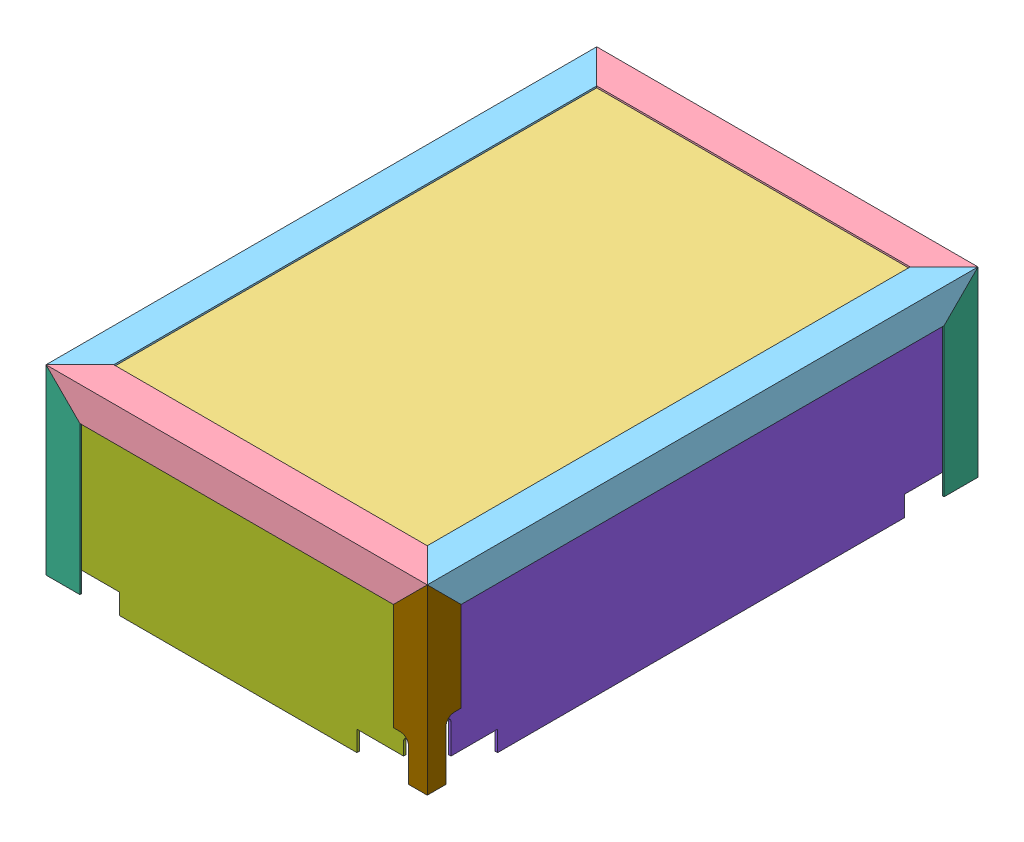
SolidWorks assembly couvercle, configuration Défaut. Lengths in mm.
Overall size (450 215 650).
13 component instances, 9 part files, 32 mates.
Components (placement in the parent):
- plaque_acrylique_680x210-2: plaque_acrylique_680x210 [Défaut] at (-694.8689 33.91 -173.3892) x (0 0 -1) z (1 0 0) size (640 210 3)
- plaque_acrylique_380x210-2: plaque_acrylique_380x210 [Défaut] at (-441.8689 33.91 -516.3892) size (440 210 3)
- plaque_acrylique_380x680-1: plaque_acrylique_380x680 [Défaut] at (-441.8689 138.91 -173.3892) x (1 0 0) z (0 1 0) size (440 640 3)
- eclisse_40x40x404_bisote_x2-1: eclisse_40x40x404_bisote_x2 [Défaut] at (-246.8689 123.7964 -498.3892) x (0 0 1) z (0 -1 0) size (40 450 40)
- eclisse_40x40x704_bisote_x2-1: eclisse_40x40x704_bisote_x2 [Défaut] at (-266.9825 123.91 -518.3892) x (0 -1 0) z (-1 0 0) size (40 650 40)
- eclisse_40x40x404_bisote_x2-2: eclisse_40x40x404_bisote_x2 [Défaut] at (-696.8689 123.7964 111.6108) x (0 0 -1) z (0 -1 0) size (40 450 40)
- eclisse_40x40x704_bisote_x2-2: eclisse_40x40x704_bisote_x2 [Défaut] at (-676.8689 123.7964 -518.3892) x (1 0 0) z (0 -1 0) size (40 650 40)
- eclisse_40x40x222_bisote_x1-1: eclisse_40x40x222_bisote_x1 [Défaut] at (-676.7552 143.91 -498.3892) x (0 0 1) z (1 0 0) size (40 215 40)
- eclisse_40x40x222_bisote_x1-2: eclisse_40x40x222_bisote_x1 [Défaut] at (-266.8689 143.91 -498.2755) x (-1 0 0) z (0 0 1) size (40 215 40)
- eclisse_40x40x222_bisote_x1-4: eclisse_40x40x222_bisote_x1 [Défaut] at (-676.8689 143.91 111.4972) x (1 0 0) z (0 0 -1) size (40 215 40)
- plaque_acrylique_380x210_Moteur-1: plaque_acrylique_380x210_Moteur [Défaut] at (-441.8689 33.91 126.6108) size (440 210 3)
- plaque_acrylique_680x210_moteur-1: plaque_acrylique_680x210_moteur [Défaut] at (-251.8689 33.91 -173.3892) x (0 0 -1) z (1 0 0) size (640 210 3)
- eclisse_40x40x222_bisote_x1_Moteur-1: eclisse_40x40x222_bisote_x1_Moteur [Défaut] at (-266.9825 143.91 111.6108) x (0 0 -1) z (-1 0 0) size (40 215 40)
Mates (geometry in assembly coordinates):
- Coïncidente1: coincident anti-aligned: plane of plaque_acrylique_380x680-1 through (-441.8689 141.91 -173.3892) normal (0 1 0); plane of eclisse_40x40x704_bisote_x2-1 through (-248.8689 141.91 131.6108) normal (0 -1 0)
- Coïncidente2: coincident anti-aligned: plane of eclisse_40x40x704_bisote_x2-1 through (-248.8689 141.91 131.6108) normal (-1 0 0); plane of plaque_acrylique_680x210_moteur-1 through (-248.8689 33.91 -173.3892) normal (1 0 0)
- Coïncidente3: coincident anti-aligned: plane of plaque_acrylique_380x210-2 through (-441.8689 33.91 -516.3892) normal (0 0 -1); plane of eclisse_40x40x404_bisote_x2-1 through (-696.8689 141.91 -516.3892) normal (0 0 1)
- Coïncidente4: coincident anti-aligned: plane of plaque_acrylique_380x680-1 through (-441.8689 141.91 -173.3892) normal (0 1 0); plane of eclisse_40x40x404_bisote_x2-1 through (-696.8689 141.91 -516.3892) normal (0 -1 0)
- Coïncidente5: coincident anti-aligned: plane of plaque_acrylique_680x210-2 through (-694.8689 33.91 -173.3892) normal (-1 0 0); plane of eclisse_40x40x704_bisote_x2-2 through (-694.8689 141.91 131.6108) normal (1 0 0)
- Coïncidente6: coincident anti-aligned: plane of plaque_acrylique_380x680-1 through (-441.8689 141.91 -173.3892) normal (0 1 0); plane of eclisse_40x40x704_bisote_x2-2 through (-694.8689 141.91 131.6108) normal (0 -1 0)
- Coïncidente7: coincident anti-aligned: plane of eclisse_40x40x404_bisote_x2-2 through (-246.8689 141.91 129.6108) normal (0 0 -1); plane of plaque_acrylique_380x210_Moteur-1 through (-441.8689 33.91 129.6108) normal (0 0 1)
- Coïncidente9: coincident anti-aligned: plane of plaque_acrylique_380x210_Moteur-1 through (-441.8689 33.91 129.6108) normal (0 0 1); plane of eclisse_40x40x222_bisote_x1_Moteur-1 through (-248.8689 -71.09 129.6108) normal (0 0 -1)
- Coïncidente10: coincident anti-aligned: plane of plaque_acrylique_680x210_moteur-1 through (-248.8689 33.91 -173.3892) normal (1 0 0); plane of eclisse_40x40x222_bisote_x1_Moteur-1 through (-248.8689 -71.09 129.6108) normal (-1 0 0)
- Coïncidente11: coincident anti-aligned: plane of plaque_acrylique_380x210-2 through (-441.8689 33.91 -516.3892) normal (0 0 -1); plane of eclisse_40x40x222_bisote_x1-2 through (-248.8689 -71.09 -516.3892) normal (0 0 1)
- Coïncidente12: coincident anti-aligned: plane of eclisse_40x40x222_bisote_x1-2 through (-248.8689 -71.09 -516.3892) normal (-1 0 0); plane of plaque_acrylique_680x210_moteur-1 through (-248.8689 33.91 -173.3892) normal (1 0 0)
- Coïncidente13: coincident anti-aligned: plane of plaque_acrylique_680x210-2 through (-694.8689 33.91 -173.3892) normal (-1 0 0); plane of eclisse_40x40x222_bisote_x1-1 through (-694.8689 -71.09 -516.3892) normal (1 0 0)
- Coïncidente14: coincident anti-aligned: plane of plaque_acrylique_380x210-2 through (-441.8689 33.91 -516.3892) normal (0 0 -1); plane of eclisse_40x40x222_bisote_x1-1 through (-694.8689 -71.09 -516.3892) normal (0 0 1)
- Coïncidente15: coincident anti-aligned: plane of eclisse_40x40x222_bisote_x1-4 through (-694.8689 -71.09 129.6108) normal (0 0 -1); plane of plaque_acrylique_380x210_Moteur-1 through (-441.8689 33.91 129.6108) normal (0 0 1)
- Coïncidente16: coincident anti-aligned: plane of plaque_acrylique_680x210-2 through (-694.8689 33.91 -173.3892) normal (-1 0 0); plane of eclisse_40x40x222_bisote_x1-4 through (-694.8689 -71.09 129.6108) normal (1 0 0)
- Coïncidente19: coincident anti-aligned: line of plaque_acrylique_380x210_Moteur-1 through (-251.8689 -47.09 126.6108) axis (0 1 0); line of plaque_acrylique_680x210_moteur-1 through (-251.8689 138.91 126.6108) axis (0 -1 0)
- Coïncidente20: coincident aligned: plane of plaque_acrylique_380x210_Moteur-1 through (-251.8689 -47.09 126.6108) normal (0 -1 0); plane of plaque_acrylique_680x210_moteur-1 through (-251.8689 -47.09 126.6108) normal (0 -1 0)
- Coïncidente21: coincident aligned: line of plaque_acrylique_680x210-2 through (-691.8689 138.91 126.6108) axis (0 -1 0); line of plaque_acrylique_380x210_Moteur-1 through (-691.8689 138.91 126.6108) axis (0 -1 0)
- Coïncidente22: coincident aligned: plane of plaque_acrylique_680x210-2 through (-694.8689 -47.09 126.6108) normal (0 -1 0); plane of plaque_acrylique_380x210_Moteur-1 through (-691.8689 -47.09 126.6108) normal (0 -1 0)
- Coïncidente23: coincident anti-aligned: line of plaque_acrylique_680x210-2 through (-691.8689 -47.09 -513.3892) axis (0 1 0); line of plaque_acrylique_380x210-2 through (-691.8689 138.91 -513.3892) axis (0 -1 0)
- Coïncidente24: coincident aligned: plane of plaque_acrylique_680x210-2 through (-694.8689 -47.09 -513.3892) normal (0 -1 0); plane of plaque_acrylique_380x210-2 through (-691.8689 -47.09 -516.3892) normal (0 -1 0)
- Coïncidente28: coincident anti-aligned: line of plaque_acrylique_380x680-1 through (-691.8689 138.91 126.6108) axis (1 0 0); line of plaque_acrylique_380x210_Moteur-1 through (-251.8689 138.91 126.6108) axis (-1 0 0)
- Coïncidente29: coincident aligned: line of plaque_acrylique_680x210-2 through (-691.8689 138.91 -513.3892) axis (0 0 1); line of plaque_acrylique_380x680-1 through (-691.8689 138.91 -513.3892) axis (0 0 1)
- Coïncidente30: coincident anti-aligned: plane of plaque_acrylique_380x680-1 through (-441.8689 141.91 -173.3892) normal (0 1 0); plane of eclisse_40x40x404_bisote_x2-2 through (-246.8689 141.91 129.6108) normal (0 -1 0)
- Coïncidente31: coincident anti-aligned: line of eclisse_40x40x404_bisote_x2-2 through (-246.8689 143.91 131.6108) axis (-0.707107 -0.707107 0); line of eclisse_40x40x222_bisote_x1_Moteur-1 through (-286.8689 103.91 131.6108) axis (0.707107 0.707107 0)
- Coïncidente32: coincident anti-aligned: line of eclisse_40x40x704_bisote_x2-1 through (-246.8689 103.91 91.6108) axis (0 0.707107 0.707107); line of eclisse_40x40x222_bisote_x1_Moteur-1 through (-246.8689 143.91 131.6108) axis (0 -0.707107 -0.707107)
- Coïncidente35: coincident anti-aligned: line of eclisse_40x40x404_bisote_x2-2 through (-656.8689 103.91 131.6108) axis (-0.707107 0.707107 0); line of eclisse_40x40x222_bisote_x1-4 through (-696.8689 143.91 131.6108) axis (0.707107 -0.707107 0)
- Coïncidente36: coincident anti-aligned: line of eclisse_40x40x704_bisote_x2-2 through (-696.8689 143.91 131.6108) axis (0 -0.707107 -0.707107); line of eclisse_40x40x222_bisote_x1-4 through (-696.8689 103.91 91.6108) axis (0 0.707107 0.707107)
- Coïncidente37: coincident anti-aligned: line of eclisse_40x40x404_bisote_x2-2 through (-696.8689 143.91 131.6108) axis (0.707107 0 -0.707107); line of eclisse_40x40x704_bisote_x2-2 through (-656.8689 143.91 91.6108) axis (-0.707107 0 0.707107)
- Coïncidente38: coincident anti-aligned: line of eclisse_40x40x404_bisote_x2-1 through (-656.8689 143.91 -478.3892) axis (-0.707107 0 -0.707107); line of eclisse_40x40x704_bisote_x2-2 through (-696.8689 143.91 -518.3892) axis (0.707107 0 0.707107)
- Coïncidente39: coincident anti-aligned: line of eclisse_40x40x704_bisote_x2-2 through (-696.8689 103.91 -478.3892) axis (0 0.707107 -0.707107); line of eclisse_40x40x222_bisote_x1-1 through (-696.8689 143.91 -518.3892) axis (0 -0.707107 0.707107)
- Coïncidente40: coincident anti-aligned: line of eclisse_40x40x404_bisote_x2-1 through (-286.8689 103.91 -518.3892) axis (0.707107 0.707107 0); line of eclisse_40x40x222_bisote_x1-2 through (-246.8689 143.91 -518.3892) axis (-0.707107 -0.707107 0)
